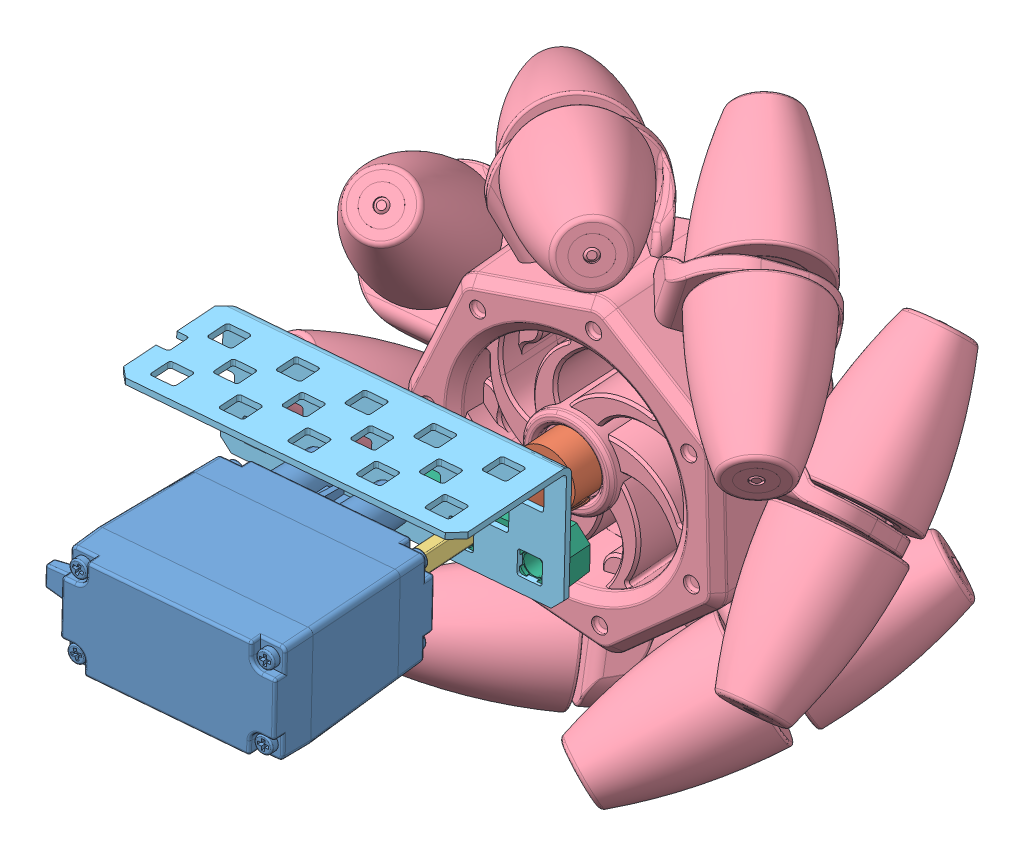
SolidWorks assembly wheel_motor_1, configuration Default. Lengths in mm.
Overall size (151.87 148.77 129.43).
8 component instances, 6 part files, 19 mates.
Components (placement in the parent):
- vex_motor269-1: vex_motor269 [Default] at (-322.0413 281.3713 21.0961) x (0.995892 -0.003261 -0.090486) z (0.090539 0.024932 0.995581) size (46.4 20 51.81)
- SHAFT-COLLAR-1: SHAFT-COLLAR [Default] at (-316.9287 279.6617 -45.4121) x (-0.826988 -0.555113 0.089108) z (-0.090539 -0.024932 -0.995581) size (11 11.46 6.6)
- SHAFT-COLLAR-2: SHAFT-COLLAR [Default] at (-319.6814 278.9037 -75.6817) x (0.985086 -0.149117 -0.08585) z (0.090539 0.024932 0.995581) size (11 11.46 6.6)
- SHAFT-4000-1: SHAFT-4000 [Default] at (-317.6837 279.4564 -53.6811) x (-0.959833 -0.26439 0.093909) z (0.090539 0.024932 0.995581) size (4.18 4.18 76.3)
- SHAFT-COLLAR-5: SHAFT-COLLAR [Default] at (-315.917 279.9403 -34.2878) x (-0.916366 -0.389369 0.093086) z (-0.090539 -0.024932 -0.995581) size (11 11.46 6.6)
- vex_mecanum_1-1: vex_mecanum_1 [Default] at (-300.2063 284.2665 138.4697) x (-0.265563 0.964094 0.000007) z (-0.959833 -0.26439 0.093909) size (120.03 63.14 119.06)
- angle-1: angle [Default] at (-345.0813 301.1798 50.1286) x (0.995892 -0.003261 -0.090486) z (0.090539 0.024932 0.995581) size (63.5 25.4 25.4)
- BEARING-FLAT-1: BEARING-FLAT [Default] at (-296.7895 265.2135 -115.3348) x (0.090539 0.024932 0.995581) z (-0.00099 -0.999684 0.025124) size (7.04 35.56 10.16)
Mates (geometry in assembly coordinates):
- Coincident45: coincident aligned: plane of SHAFT-COLLAR-2 through (-319.9804 278.8214 -78.9691) normal (-0.090539 -0.024932 -0.995581); plane of SHAFT-4000-1 through (-317.8324 288.1415 -79.3979) normal (-0.090539 -0.024932 -0.995581)
- Coincident25: coincident anti-aligned: plane of vex_motor269-1 through (-311.0903 279.6256 -3.2595) normal (-0.265563 0.964094 0.000007); plane of SHAFT-4000-1 through (-311.139 279.6121 -3.2547) normal (0.265563 -0.964094 -0.000007)
- Coincident26: coincident anti-aligned: plane of vex_motor269-1 through (-315.0432 281.8827 -2.9565) normal (0.959833 0.26439 -0.093909); plane of SHAFT-4000-1 through (-315.0297 281.8337 -2.9565) normal (-0.959833 -0.26439 0.093909)
- Coincident27: coincident anti-aligned: plane of vex_motor269-1 through (-314.1865 278.7727 -2.9566) normal (-0.090539 -0.024932 -0.995581); plane of SHAFT-4000-1 through (-311.139 279.6121 -3.2547) normal (0.090539 0.024932 0.995581)
- Coincident35: coincident anti-aligned: plane of SHAFT-COLLAR-2 through (-319.3824 278.986 -72.3943) normal (0.090539 0.024932 0.995581); plane of vex_mecanum_1-1 through (-319.3824 278.986 -72.3943) normal (-0.090539 -0.024932 -0.995581)
- Concentric14: concentric aligned: cylinder of SHAFT-COLLAR-2 through (-319.9804 278.8214 -78.9691) axis (0.090539 0.024932 0.995581) radius 5.5; cylinder of vex_mecanum_1-1 through (-319.5816 278.9312 -74.5846) axis (0.090539 0.024932 0.995581) radius 6
- Distance11: distance = 0.04 mm: plane of SHAFT-4000-1 through (-311.9822 282.6731 -3.2547) normal (-0.265563 0.964094 0.000007); line of vex_mecanum_1-1 through (-318.9762 280.7057 -71.9199) axis (0.090539 0.024932 0.995581)
- Distance12: distance = 0.04 mm: line of vex_mecanum_1-1 through (-318.6153 280.8049 -50.9142) axis (-0.090539 -0.024932 -0.995581); plane of SHAFT-4000-1 through (-311.9822 282.6731 -3.2547) normal (-0.265563 0.964094 0.000007)
- Distance14: distance = 0.04 mm: line of vex_mecanum_1-1 through (-319.1361 279.8835 -50.8437) axis (-0.090539 -0.024932 -0.995581); plane of SHAFT-4000-1 through (-315.0297 281.8337 -2.9565) normal (-0.959833 -0.26439 0.093909)
- Concentric15: concentric anti-aligned: cylinder of SHAFT-COLLAR-1 through (-316.6297 279.7441 -42.1247) axis (-0.090539 -0.024932 -0.995581) radius 5.5; cylinder of vex_mecanum_1-1 through (-317.0465 279.6293 -46.7083) axis (0.090539 0.024932 0.995581) radius 6
- Coincident41: coincident anti-aligned: plane of SHAFT-COLLAR-1 through (-317.2276 279.5794 -48.6995) normal (-0.090539 -0.024932 -0.995581); plane of vex_mecanum_1-1 through (-317.2276 279.5794 -48.6995) normal (0.090539 0.024932 0.995581)
- Concentric16: concentric aligned: cylinder of SHAFT-COLLAR-1 through (-316.6297 279.7441 -42.1247) axis (-0.090539 -0.024932 -0.995581) radius 5.5; cylinder of SHAFT-COLLAR-5 through (-315.6181 280.0226 -31.0004) axis (-0.090539 -0.024932 -0.995581) radius 5.5
- Concentric17: concentric anti-aligned: cylinder of BEARING-FLAT-1 through (-302.9556 280.0142 -32.1518) axis (0.090539 0.024932 0.995581) radius 2.1209; circle of angle-1
- Concentric18: concentric anti-aligned: cylinder of BEARING-FLAT-1 through (-328.2513 280.097 -29.8534) axis (0.090539 0.024932 0.995581) radius 2.1209; circle of angle-1
- Concentric19: concentric aligned: circle of vex_motor269-1; circle of angle-1
- Concentric20: concentric anti-aligned: circle of vex_motor269-1; circle of angle-1
- Coincident42: coincident aligned: circle of vex_motor269-1; plane of angle-1 through (-295.9322 299.2249 -25.7198) normal (0.090539 0.024932 0.995581)
- Coincident43: coincident anti-aligned: plane of angle-1 through (-296.0379 299.1958 -26.883) normal (-0.090539 -0.024932 -0.995581); plane of BEARING-FLAT-1 through (-332.7342 285.354 -23.1992) normal (0.090539 0.024932 0.995581)
- Coincident44: coincident anti-aligned: plane of SHAFT-COLLAR-5 through (-315.6181 280.0226 -31.0004) normal (0.090539 0.024932 0.995581); plane of BEARING-FLAT-1 through (-321.6688 286.0367 -30.6008) normal (-0.090539 -0.024932 -0.995581)
